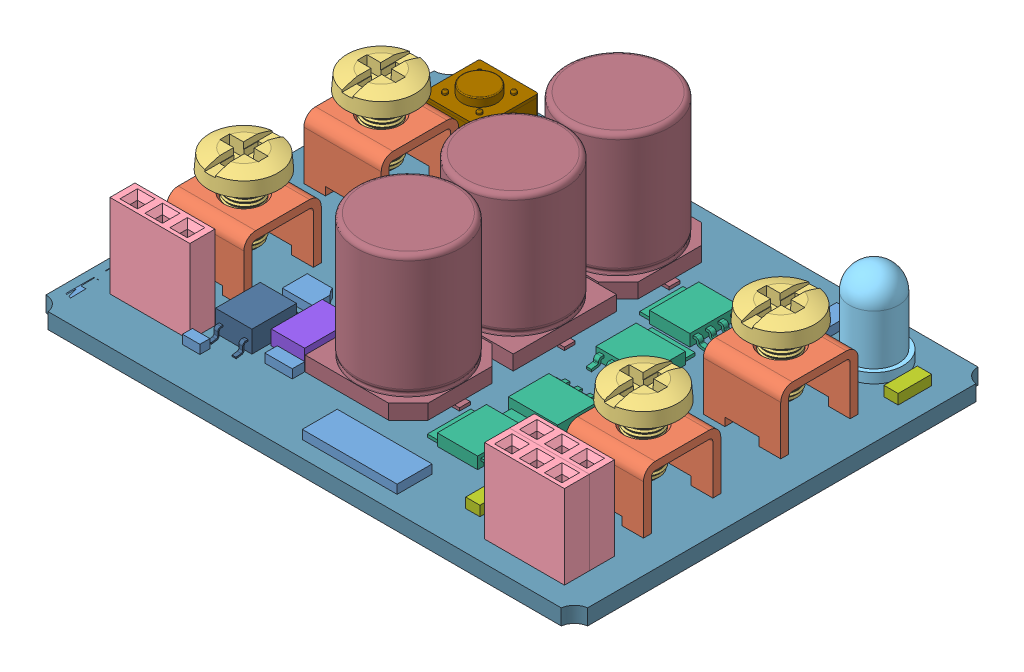
SolidWorks assembly RR-SPARK-BD-B-Assembly, configuration Default. Lengths in mm.
Overall size (55.12 26.11 42.42).
32 component instances, 14 part files, 0 mates.
Components (placement in the parent):
- RR-SPARK-BD-B-1: RR-SPARK-BD-B [Default] at (27.8945 25.8332 38.0904) size (53.34 3.8 40.64)
- ScrewTerminalAssembly-1: ScrewTerminalAssembly [Default] at (15.7541 22.7195 39.4261) x (0 0 1) z (-1 0 0) size (7.87 11.69 7.87)
  - ScrewTerminalBase-1: ScrewTerminalBase [Default] at (3.4868 6.6312 8.3972) size (7.87 7.68 7.87)
  - ScrewTerminalScrew-1: ScrewTerminalScrew [Default] at (3.5041 -1.1314 8.5263) x (0.998152 0 -0.060771) z (0.060771 0 0.998152) size (7.16 8.3 7.16)
- ScrewTerminalAssembly-2: ScrewTerminalAssembly [Default] at (56.3941 22.7195 39.4261) x (0 0 1) z (-1 0 0) size (7.87 11.69 7.87)
  - ScrewTerminalBase-1: ScrewTerminalBase [Default] at (3.4868 6.6312 8.3972) size (7.87 7.68 7.87)
  - ScrewTerminalScrew-1: ScrewTerminalScrew [Default] at (3.5041 -1.1314 8.5263) x (0.998152 0 -0.060771) z (0.060771 0 0.998152) size (7.16 8.3 7.16)
- ScrewTerminalAssembly-3: ScrewTerminalAssembly [Default] at (15.7541 22.7195 25.4561) x (0 0 1) z (-1 0 0) size (7.87 11.69 7.87)
  - ScrewTerminalBase-1: ScrewTerminalBase [Default] at (3.4868 6.6312 8.3972) size (7.87 7.68 7.87)
  - ScrewTerminalScrew-1: ScrewTerminalScrew [Default] at (3.5041 -1.1314 8.5263) x (0.998152 0 -0.060771) z (0.060771 0 0.998152) size (7.16 8.3 7.16)
- ScrewTerminalAssembly-4: ScrewTerminalAssembly [Default] at (56.3941 22.7195 25.4561) x (0 0 1) z (-1 0 0) size (7.87 11.69 7.87)
  - ScrewTerminalBase-1: ScrewTerminalBase [Default] at (3.4868 6.6312 8.3972) size (7.87 7.68 7.87)
  - ScrewTerminalScrew-1: ScrewTerminalScrew [Default] at (3.5041 -1.1314 8.5263) x (0.998152 0 -0.060771) z (0.060771 0 0.998152) size (7.16 8.3 7.16)
- Header-Female-1x3-PPTC031LFBN-RC-1: Header-Female-1x3-PPTC031LFBN-RC [Default] at (7.5745 27.4332 53.3304) size (8.13 15.71 2.54)
- Header-Female-1x3-PPTC031LFBN-RC-2: Header-Female-1x3-PPTC031LFBN-RC [Default] at (48.2145 27.4332 53.3304) size (8.13 15.71 2.54)
- Header-Female-1x3-PPTC031LFBN-RC-3: Header-Female-1x3-PPTC031LFBN-RC [Default] at (48.2145 27.4332 55.8704) size (8.13 15.71 2.54)
- LED-RGB-ThroughHole-1: LED-RGB-ThroughHole [Default] at (48.2145 27.4332 21.5804) x (-1 0 0) z (0 0 -1) size (5.45 12.2 5.9)
- MOSFET-PSMN1R0-30YLC115-1: MOSFET-PSMN1R0-30YLC115 [Default] at (35.6415 27.4332 27.2954) x (0 0 -1) z (1 0 0) size (5 1.2 6.72)
- MOSFET-PSMN1R0-30YLC115-2: MOSFET-PSMN1R0-30YLC115 [Default] at (36.5305 27.4332 33.6454) size (5 1.2 6.72)
- MOSFET-PSMN1R0-30YLC115-3: MOSFET-PSMN1R0-30YLC115 [Default] at (36.5305 27.4332 42.5354) x (-1 0 0) z (0 0 -1) size (5 1.2 6.72)
- MOSFET-PSMN1R0-30YLC115-4: MOSFET-PSMN1R0-30YLC115 [Default] at (35.6415 27.4332 48.8854) x (0 0 -1) z (1 0 0) size (5 1.2 6.72)
- Varistor-1: Varistor [Default] at (52.6595 27.4332 22.5964) x (0 0 1) z (-1 0 0) size (3.4 1.02 1.45)
- Varistor-2: Varistor [Default] at (41.2295 27.4332 53.7114) x (0 0 1) z (-1 0 0) size (3.4 1.02 1.45)
- Crystal-1: Crystal [Default] at (17.9885 27.4332 48.3774) x (0 0 1) z (-1 0 0) size (5.2 1.5 3.4)
- Button-PTS645SM43SMTR92LFS-1: Button-PTS645SM43SMTR92LFS [Default] at (8.0825 27.4332 21.5804) size (9 4.3 6)
- OptoIsolator-TLP118-1: OptoIsolator-TLP118 [Default] at (14.1785 27.4332 50.4094) x (0 0 -1) z (1 0 0) size (7.02 2.2 3.7)
- GateDriver-A4940KLPTR-T-1: GateDriver-A4940KLPTR-T [Default] at (30.1805 25.8332 53.9654) x (0 0 -1) z (-1 0 0) size (7.8 1.2 6.43)
- MCU-PIC16F1828-I-GZ-1: MCU-PIC16F1828-I-GZ [Default] at (19.0045 25.8332 52.8224) x (-1 0 0) z (0 0 1) size (4 0.55 4)
- Capacitor-UCL1V471MNL1GS-1: Capacitor-UCL1V471MNL1GS [Default] at (25.8625 27.4332 46.5994) x (0 0 1) z (-1 0 0) size (10.5 14.3 11.5)
- Capacitor-UCL1V471MNL1GS-2: Capacitor-UCL1V471MNL1GS [Default] at (25.8625 27.4332 25.2634) x (0 0 1) z (-1 0 0) size (10.5 14.3 11.5)
- Capacitor-UCL1V471MNL1GS-3: Capacitor-UCL1V471MNL1GS [Default] at (25.8625 27.4332 35.9314) x (0 0 -1) z (1 0 0) size (10.5 14.3 11.5)
- 1mmborder-1: 1mmborder [Default] at (27.8945 25.8332 38.0904) size (55.12 1.6 42.42)
